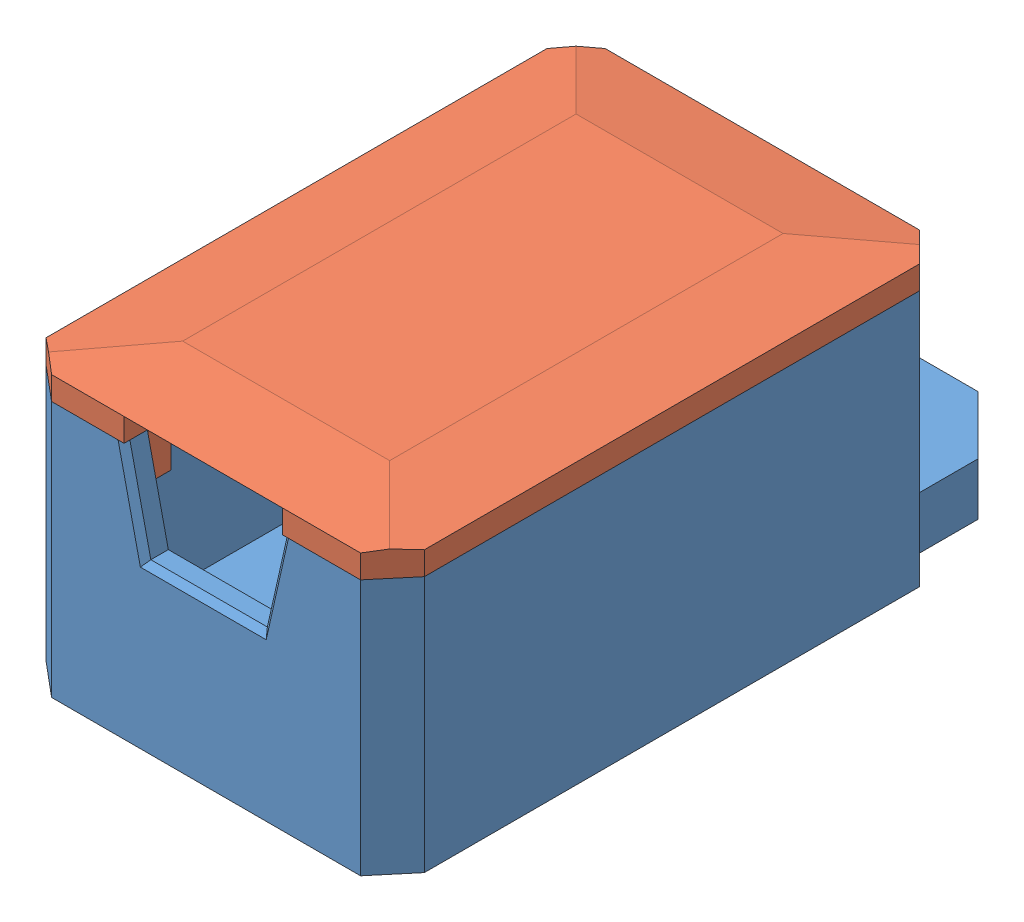
SolidWorks assembly lap_rap_cambienroi, configuration Default. Lengths in mm.
Overall size (32 25 58).
2 component instances, 2 part files, 4 mates.
Components (placement in the parent):
- cam_bien_roi-1: cam_bien_roi [Default] at origin size (32 22 58)
- nap_cambien_roi-1: nap_cambien_roi [Default] at (0 22 0) size (32 7 48)
Mates (geometry in assembly coordinates):
- Parallel1: parallel aligned: plane of cam_bien_roi-1 through (0 2 0) normal (0 1 0); plane of nap_cambien_roi-1 through (0 25 0) normal (0 1 0)
- Width1: width anti-aligned: plane of nap_cambien_roi-1 through (-13.95 18 21.95) normal (-1 0 0); plane of nap_cambien_roi-1 through (13.95 18 -21.95) normal (1 0 0); plane of cam_bien_roi-1 through (-14 22 -24) normal (1 0 0); plane of cam_bien_roi-1 through (14 22 -24) normal (-1 0 0)
- Coincident1: coincident aligned: plane of cam_bien_roi-1 through (-16 22 24) normal (0 0 1); plane of nap_cambien_roi-1 through (-16 25 24) normal (0 0 1)
- Coincident2: coincident anti-aligned: plane of cam_bien_roi-1 through (0 22 0) normal (0 1 0); plane of nap_cambien_roi-1 through (0 22 0) normal (0 -1 0)
